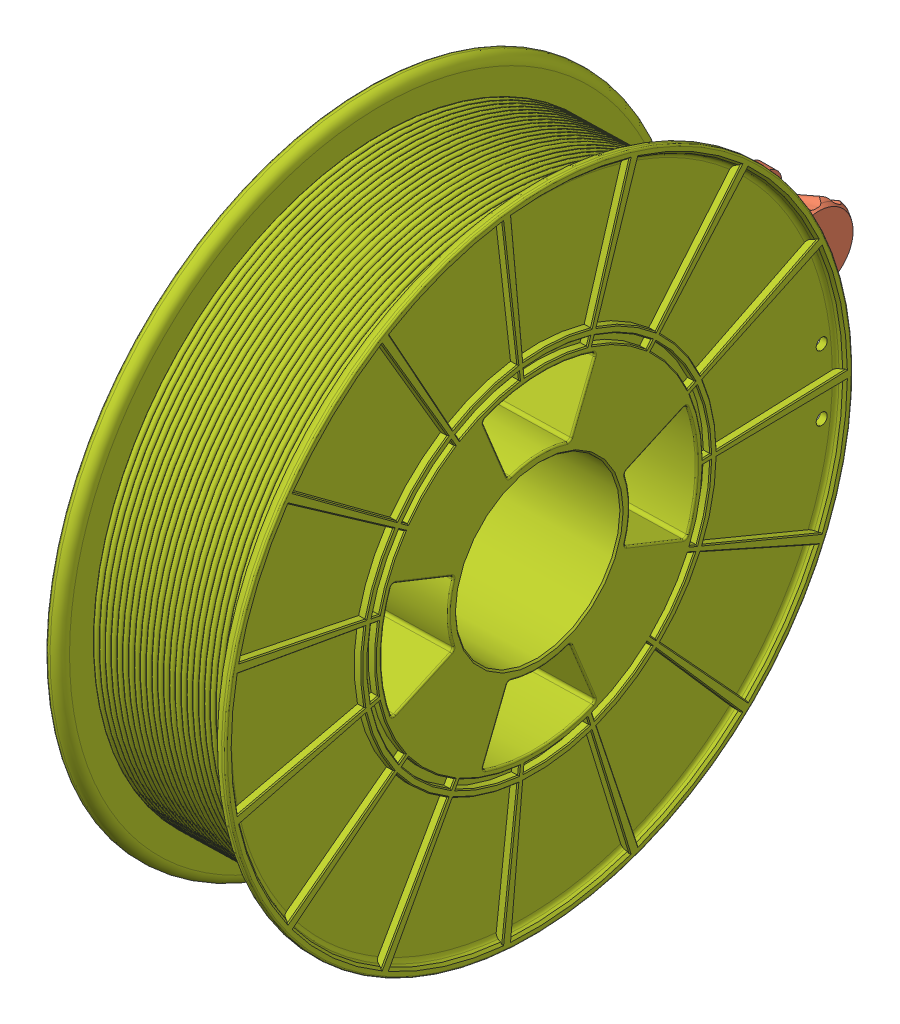
SolidWorks assembly Mini Spool Holder, configuration Default. Lengths in mm.
Overall size (71.98 198 238.05).
11 component instances, 8 part files, 27 mates.
Components (placement in the parent):
- Datum-1: Datum [Default] at origin size (20 20 500) (hidden)
- Mini Spool Holder Hub-1: Mini Spool Holder Hub [Default] at (17 0 272) x (0 -1 0) z (1 0 0) size (50.35 50.35 29)
- Mini Spool Holder Top Idler V3-1: Mini Spool Holder Top Idler V3 [Default] at (45 10 185) x (0 0 -1) z (0 -1 0) size (48.54 34 23.39)
- 91239A236_CLASS 10.9 STL BUTTON-HEAD SOCKET CAP SCREW-1: 91239A236_CLASS 10.9 STL BUTTON-HEAD SOCKET CAP SCREW [91239A236] at (38.925 0 272) x (0 -1 0) z (1 0 0) size (9.5 9.5 33.32)
- 91290A228_BLACK-OXIDE CLASS 12.9 SOCKET HEAD CAP SCREW-1: 91290A228_BLACK-OXIDE CLASS 12.9 SOCKET HEAD CAP SCREW [91290A228] at (5.3 0 158) x (0 0.837169 -0.546944) z (-1 0 0) size (8.5 8.5 17.42)
- 5972K501_BALL BEARING-1: 5972K501_BALL BEARING [5972K501] at (33 0 189.5) x (0 -1 0) z (0 0 1) size (22 22 7)
- 5972K501_BALL BEARING-2: 5972K501_BALL BEARING [5972K501] at (30.675 0 272) x (0 -1 0) z (1 0 0) size (22 22 7)
- 5972K501_BALL BEARING-3: 5972K501_BALL BEARING [5972K501] at (18.5 0 272) x (0 -1 0) z (1 0 0) size (22 22 7)
- Spring Loaded Tee Nut-1: Spring Loaded Tee Nut [Default] at (8.8 0 153.8) x (0 -1 0) z (0 0 1) size (8.3 4.2 13.6)
- Spring Loaded Tee Nut-2: Spring Loaded Tee Nut [Default] at (8.8 0 267.8) x (0 -1 0) z (0 0 1) size (8.3 4.2 13.6)
- Spool-1: Spool [Default] at (74.0703 0 283.7262) x (0.99968 0 -0.025294) z (0 1 0) size (54 198 198)
Mates (geometry in assembly coordinates):
- Coincident1: coincident aligned: plane of Datum-1 through (0 0 0) normal (0 0 1); plane of assembly through (0 0 0) normal (0 0 1)
- Coincident2: coincident aligned: plane of Datum-1 through (0 0 0) normal (0 1 0); plane of assembly through (0 0 0) normal (0 1 0)
- Coincident3: coincident aligned: plane of Datum-1 through (0 0 0) normal (1 0 0); plane of assembly through (0 0 0) normal (1 0 0)
- Concentric1: concentric anti-aligned: cylinder of Mini Spool Holder Top Idler V3-1 through (33 0 211.0723) axis (0 0 -1) radius 3.95; cylinder of 5972K501_BALL BEARING-1 through (33 0 193) axis (0 0 1) radius 4
- Coincident4: coincident anti-aligned: plane of Mini Spool Holder Top Idler V3-1 through (33 0 186) normal (0 0 1); plane of 5972K501_BALL BEARING-1 through (37.35 0 186) normal (0 0 -1)
- Concentric2: concentric anti-aligned: cylinder of Mini Spool Holder Hub-1 through (24 0 272) axis (-1 0 0) radius 3.875; cylinder of 5972K501_BALL BEARING-3 through (22 0 272) axis (1 0 0) radius 4
- Coincident5: coincident anti-aligned: plane of Mini Spool Holder Hub-1 through (15 0 272) normal (1 0 0); plane of 5972K501_BALL BEARING-3 through (15 0 267.65) normal (-1 0 0)
- Concentric3: concentric aligned: cylinder of Mini Spool Holder Hub-1 through (13.0398 0 272) axis (1 0 0) radius 3.875; cylinder of 5972K501_BALL BEARING-2 through (34.175 0 272) axis (1 0 0) radius 4
- Coincident6: coincident anti-aligned: plane of Mini Spool Holder Hub-1 through (27.175 -7 272) normal (1 0 0); plane of 5972K501_BALL BEARING-2 through (27.175 0 261.35) normal (-1 0 0)
- Concentric4: concentric anti-aligned: cylinder of Mini Spool Holder Hub-1 through (13.0398 0 272) axis (1 0 0) radius 2.65; cylinder of 91239A236_CLASS 10.9 STL BUTTON-HEAD SOCKET CAP SCREW-1 through (6.175 0 272) axis (-1 0 0) radius 2.5
- Coincident7: coincident anti-aligned: plane of Mini Spool Holder Hub-1 through (36.175 0 272) normal (1 0 0); plane of 91239A236_CLASS 10.9 STL BUTTON-HEAD SOCKET CAP SCREW-1 through (36.175 0 276.75) normal (-1 0 0)
- Concentric5: concentric aligned: cylinder of Mini Spool Holder Top Idler V3-1 through (17 0 158) axis (-1 0 0) radius 2.65; cylinder of 91290A228_BLACK-OXIDE CLASS 12.9 SOCKET HEAD CAP SCREW-1 through (17.3 0 158) axis (-1 0 0) radius 2.5
- Coincident8: coincident anti-aligned: plane of Mini Spool Holder Top Idler V3-1 through (22.3 0 158) normal (-1 0 0); plane of 91290A228_BLACK-OXIDE CLASS 12.9 SOCKET HEAD CAP SCREW-1 through (22.3 0 158) normal (1 0 0)
- Coincident9: coincident anti-aligned: plane of Datum-1 through (0 0 0) normal (0 1 0); plane of Mini Spool Holder Top Idler V3-1 through (45 0 185) normal (0 -1 0)
- Coincident10: coincident anti-aligned: plane of Mini Spool Holder Hub-1 through (17 0 272) normal (0 -1 0); plane of Datum-1 through (0 0 0) normal (0 1 0)
- Coincident15: coincident: line of Datum-1 through (10 -4.58 500) axis (0 0 -1); plane of Mini Spool Holder Hub-1 through (10 0 272) normal (-1 0 0)
- Distance1: distance = 72 mm anti-aligned: plane of Mini Spool Holder Hub-1 through (10 -10 257) normal (0 0 -1); plane of Mini Spool Holder Top Idler V3-1 through (45 -10 185) normal (0 0 1)
- Distance2: distance = 150 mm aligned: plane of Mini Spool Holder Top Idler V3-1 through (10 -10 150) normal (0 0 -1); plane of Datum-1 through (0 0 0) normal (0 0 -1)
- Concentric6: concentric anti-aligned: cylinder of 91290A228_BLACK-OXIDE CLASS 12.9 SOCKET HEAD CAP SCREW-1 through (17.3 0 158) axis (-1 0 0) radius 2.5; cylinder of Spring Loaded Tee Nut-1 through (8.8 0 158) axis (1 0 0) radius 2.1
- Distance3: distance = 1.7 mm anti-aligned: plane of Spring Loaded Tee Nut-1 through (8.3 2.8 167.4) normal (1 0 0); plane of Mini Spool Holder Top Idler V3-1 through (10 -10 185) normal (-1 0 0)
- Parallel4: parallel aligned: plane of Mini Spool Holder Top Idler V3-1 through (10 -10 150) normal (0 0 -1); plane of Spring Loaded Tee Nut-1 through (7.5 1.25 153.8) normal (0 0 -1)
- Concentric7: concentric anti-aligned: cylinder of 91239A236_CLASS 10.9 STL BUTTON-HEAD SOCKET CAP SCREW-1 through (6.175 0 272) axis (-1 0 0) radius 2.5; cylinder of Spring Loaded Tee Nut-2 through (8.8 0 272) axis (1 0 0) radius 2.1
- Distance4: distance = 1.7 mm anti-aligned: plane of Spring Loaded Tee Nut-2 through (8.3 2.8 281.4) normal (1 0 0); plane of Mini Spool Holder Hub-1 through (10 0 272) normal (-1 0 0)
- Parallel5: parallel aligned: plane of Mini Spool Holder Hub-1 through (10 -10 257) normal (0 0 -1); plane of Spring Loaded Tee Nut-2 through (7.5 1.25 267.8) normal (0 0 -1)
- Coincident23: coincident: line of Datum-1 through (10 -4.58 500) axis (0 0 -1); plane of Mini Spool Holder Top Idler V3-1 through (10 -10 185) normal (-1 0 0)
- Coincident25: coincident aligned: plane of Datum-1 through (0 0 0) normal (0 1 0); plane of Spool-1 through (74.0703 0 283.7262) normal (0 1 0)
- Tangent3: tangent anti-aligned: plane of Spool-1 through (21.908 0 189.0153) normal (0.99968 0 -0.025294); circle of 5972K501_BALL BEARING-1
